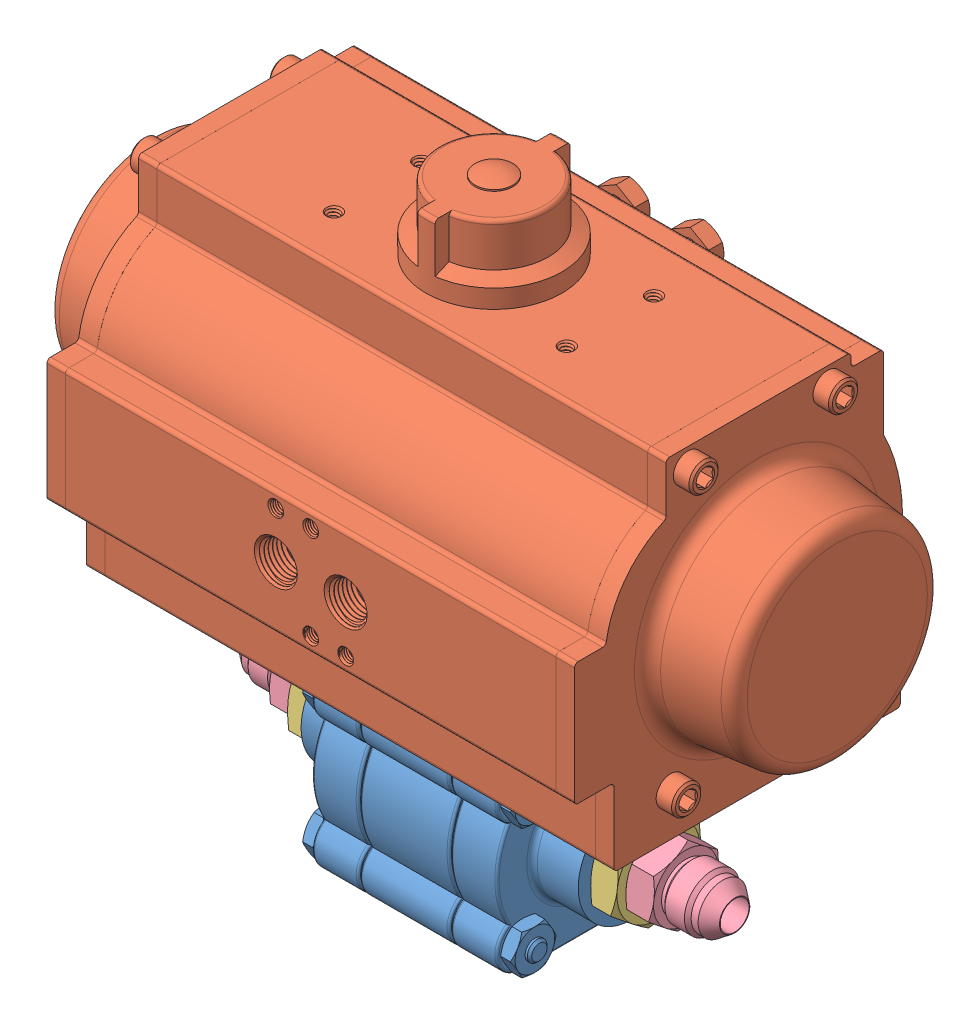
SolidWorks assembly FAKE_SOV-1,2,5, configuration Default. Lengths in mm.
Overall size (235.97 211.39 123.09).
6 component instances, 4 part files, 7 mates.
Components (placement in the parent):
- FAKE_sharpe_80BV-1: FAKE_sharpe_80BV [3778T941] at origin size (96.68 86.36 61.47)
- 49935K880_AIR ACTUATOR FOR BALL-BUTTERFLY VALVE-1: 49935K880_AIR ACTUATOR FOR BALL-BUTTERFLY VALVE [49935K88] at (0 41.529 0) x (0 0 1) z (-1 0 0) size (123.09 139.45 235.97)
- 51205K359_EXTREME-PRESSURE 316 SS THREADED PIPE FITTING-1: 51205K359_EXTREME-PRESSURE 316 SS THREADED PIPE FITTING [51205K359] at (-41.6814 0 0) x (-1 0 0) z (0 -0.924225 -0.381849) size (30.4 33 28.57)
- 0500_OD_JIC_to_0500_NPT-1: 0500_OD_JIC_to_0500_NPT [50715K802] at (-60.0964 0 0) x (-1 0 0) z (0 -0.924225 -0.381849) size (55.21 25.66 22.23)
- 0500_OD_JIC_to_0500_NPT-2: 0500_OD_JIC_to_0500_NPT [50715K802] at (60.0964 0 0) x (1 0 0) z (0 0.924225 0.381849) size (55.21 25.66 22.23)
- 51205K359_EXTREME-PRESSURE 316 SS THREADED PIPE FITTING-3: 51205K359_EXTREME-PRESSURE 316 SS THREADED PIPE FITTING [51205K359] at (41.6814 0 0) x (1 0 0) z (0 -0.924225 -0.381849) size (30.4 33 28.57)
Mates (geometry in assembly coordinates):
- Distance1: distance = 3.175 mm anti-aligned: plane of FAKE_sharpe_80BV-1 through (0 38.354 0) normal (0 1 0); plane of 49935K880_AIR ACTUATOR FOR BALL-BUTTERFLY VALVE-1 through (-90.6462 41.529 -49.022) normal (0 -1 0)
- Concentric1: concentric anti-aligned: circle of FAKE_sharpe_80BV-1; circle of 49935K880_AIR ACTUATOR FOR BALL-BUTTERFLY VALVE-1
- Parallel1: parallel aligned: line of FAKE_sharpe_80BV-1 through (-31.75 -29.972 -22.225) axis (0 0 1); line of 49935K880_AIR ACTUATOR FOR BALL-BUTTERFLY VALVE-1 through (-90.6462 41.529 -47.752) axis (0 0 1)
- Concentric2: concentric anti-aligned: cylinder of FAKE_sharpe_80BV-1 through (-31.75 0 0) axis (-1 0 0) radius 18.669; cone of 51205K359_EXTREME-PRESSURE 316 SS THREADED PIPE FITTING-1 through (-26.8224 0 0) axis (1 0 0)
- Coincident1: coincident anti-aligned: plane of FAKE_sharpe_80BV-1 through (-47.625 0 0) normal (-1 0 0); plane of 51205K359_EXTREME-PRESSURE 316 SS THREADED PIPE FITTING-1 through (-47.625 -3.7554 -28.3272) normal (1 0 0)
- Concentric3: concentric anti-aligned: cylinder of FAKE_sharpe_80BV-1 through (-31.75 0 0) axis (-1 0 0) radius 18.669; cone of 0500_OD_JIC_to_0500_NPT-1 through (-56.5404 0 0) axis (1 0 0)
- Coincident2: coincident anti-aligned: plane of 51205K359_EXTREME-PRESSURE 316 SS THREADED PIPE FITTING-1 through (-56.5404 -3.7554 -28.3272) normal (-1 0 0); plane of 0500_OD_JIC_to_0500_NPT-1 through (-56.5404 -2.9208 -22.0322) normal (1 0 0)
